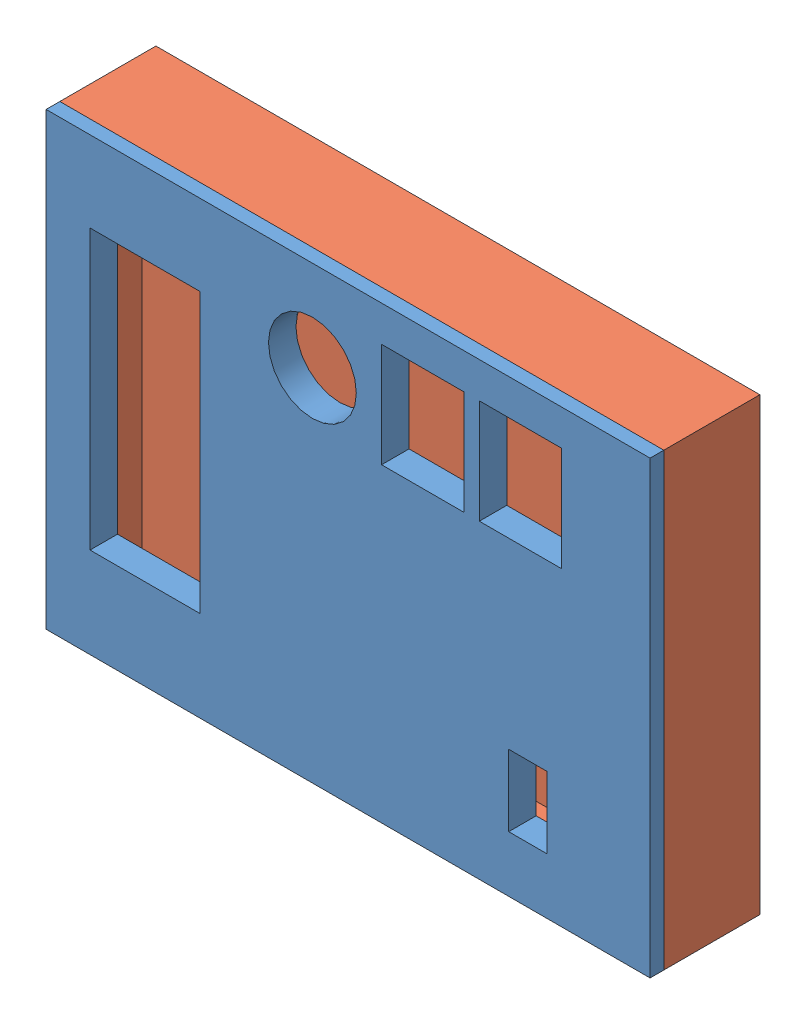
SolidWorks assembly Phase_B_Encloser_ASM.STEP, configuration Default. Lengths in mm.
Overall size (110 82 20).
50 component instances, 3 part files, 3 mates.
Components (placement in the parent):
- R_0805_2012Metric.STEP-1: R_0805_2012Metric.STEP [Default] at (136.75 -75.9525 1.63) x (0 1 0) z (0 0 1) size (2 1.2 0.45) (suppressed, hidden)
- PinSocket_2x03_P2.54mm_Vertical.STEP-1: PinSocket_2x03_P2.54mm_Vertical.STEP [Default] at (166.9225 -107.335 1.13) x (-1 0 0) z (0 0 -1) size (5.08 7.62 10.1) (suppressed, hidden)
- C_0603_1608Metric.STEP-1: C_0603_1608Metric.STEP [Default] at (175.1083 -95.3579 1.63) x (0 1 0) z (0 0 1) size (1.6 0.8 0.8) (suppressed, hidden)
- C_0603_1608Metric.STEP-2: C_0603_1608Metric.STEP [Default] at (167.3681 -95.3139 1.63) x (0 1 0) z (0 0 1) size (1.6 0.8 0.8) (suppressed, hidden)
- R_0603_1608Metric.STEP-1: R_0603_1608Metric.STEP [Default] at (178.1154 -121.5005 1.63) size (1.6 0.8 0.45) (suppressed, hidden)
- R_0805_2012Metric.STEP-2: R_0805_2012Metric.STEP [Default] at (164.6638 -86.8628 1.63) size (2 1.2 0.45) (suppressed, hidden)
- USB_Mini-B_Lumberg_2486_01_Horizontal.STEP-1: USB_Mini-B_Lumberg_2486_01_Horizontal.STEP [Default] at (156.7225 -119.07 1.63) size (9.9 9.21 5) (suppressed, hidden)
- SOT-23-5.STEP-1: SOT-23-5.STEP [Default] at (160.6831 -79.2295 1.63) x (0 -1 0) z (0 0 1) size (2.8 2.9 1.55) (suppressed, hidden)
- R_0805_2012Metric.STEP-3: R_0805_2012Metric.STEP [Default] at (124.46 -81.28 1.63) size (2 1.2 0.45) (suppressed, hidden)
- TQFP-44_10x10mm_P0.8mm.STEP-1: TQFP-44_10x10mm_P0.8mm.STEP [Default] at (154.94 -91.44 1.63) x (0 1 0) z (0 0 1) size (12 12 1.1) (suppressed, hidden)
- LED_0805_2012Metric.STEP-1: LED_0805_2012Metric.STEP [Default] at (136.66 -80.3425 1.63) x (0 1 0) z (0 0 1) size (2 1.25 1.1) (suppressed, hidden)
- C_0603_1608Metric.STEP-3: C_0603_1608Metric.STEP [Default] at (164.6143 -92.9198 1.63) size (1.6 0.8 0.8) (suppressed, hidden)
- CA56-12EWA.STEP-1: CA56-12EWA.STEP [Default] at (101.6 -81.28 1.63) size (19 50.3 12.2) (suppressed, hidden)
- C_0603_1608Metric.STEP-4: C_0603_1608Metric.STEP [Default] at (160.3412 -83.2998 1.63) x (-1 0 0) z (0 0 1) size (1.6 0.8 0.8) (suppressed, hidden)
- TSSOP-16_4.4x5mm_P0.65mm.STEP-1: TSSOP-16_4.4x5mm_P0.65mm.STEP [Default] at (137.16 -93.98 1.63) size (6.4 5 1.1) (suppressed, hidden)
- PTS125_SMD_Button.STEP-1: PTS125_SMD_Button.STEP [Default] at (177.0425 -64.155 1.63) x (0 1 0) z (1 0 0) size (12 4.3 15.3) (suppressed, hidden)
- C_0603_1608Metric.STEP-5: C_0603_1608Metric.STEP [Default] at (171.2411 -95.3579 1.63) x (0 1 0) z (0 0 1) size (1.6 0.8 0.8) (suppressed, hidden)
- R_0603_1608Metric.STEP-2: R_0603_1608Metric.STEP [Default] at (171.895 -101.6 1.63) size (1.6 0.8 0.45) (suppressed, hidden)
- C_0603_1608Metric.STEP-6: C_0603_1608Metric.STEP [Default] at (135.1928 -99.8408 1.63) x (-1 0 0) z (0 0 1) size (1.6 0.8 0.8) (suppressed, hidden)
- C_0805_2012Metric.STEP-1: C_0805_2012Metric.STEP [Default] at (177.4051 -95.4592 1.63) x (0 1 0) z (0 0 1) size (2 1.25 1.25) (suppressed, hidden)
- R_0805_2012Metric.STEP-4: R_0805_2012Metric.STEP [Default] at (124.46 -96.93 1.63) size (2 1.2 0.45) (suppressed, hidden)
- R_0805_2012Metric.STEP-5: R_0805_2012Metric.STEP [Default] at (124.46 -99.88 1.63) size (2 1.2 0.45) (suppressed, hidden)
- Buzzer_12x9.5RM7.6.STEP-1: Buzzer_12x9.5RM7.6.STEP [Default] at (139.7 -67.955 1.63) x (0 1 0) z (0 0 1) size (12 12 12.53) (suppressed, hidden)
- R_0603_1608Metric.STEP-3: R_0603_1608Metric.STEP [Default] at (164.621 -94.7272 1.63) x (-1 0 0) z (0 0 1) size (1.6 0.8 0.45) (suppressed, hidden)
- LED_0805_2012Metric.STEP-2: LED_0805_2012Metric.STEP [Default] at (139.7 -80.3425 1.63) x (0 1 0) z (0 0 1) size (2 1.25 1.1) (suppressed, hidden)
- R_0603_1608Metric.STEP-4: R_0603_1608Metric.STEP [Default] at (157.3461 -113.1038 1.63) x (0 1 0) z (0 0 1) size (1.6 0.8 0.45) (suppressed, hidden)
- R_0805_2012Metric.STEP-6: R_0805_2012Metric.STEP [Default] at (164.6674 -88.9903 1.63) size (2 1.2 0.45) (suppressed, hidden)
- C_0603_1608Metric.STEP-7: C_0603_1608Metric.STEP [Default] at (173.1422 -95.3579 1.63) x (0 1 0) z (0 0 1) size (1.6 0.8 0.8) (suppressed, hidden)
- C_0603_1608Metric.STEP-8: C_0603_1608Metric.STEP [Default] at (183.7777 -121.5005 1.63) size (1.6 0.8 0.8) (suppressed, hidden)
- Crystal_SMD_Abracon_ABM8G-4Pin_3.2x2.5mm.STEP-1: Crystal_SMD_Abracon_ABM8G-4Pin_3.2x2.5mm.STEP [Default] at (160.167 -106.8176 1.63) x (0 1 0) z (0 0 1) size (3.2 2.5 0.64) (suppressed, hidden)
- R_0805_2012Metric.STEP-7: R_0805_2012Metric.STEP [Default] at (124.46 -78.33 1.63) size (2 1.2 0.45) (suppressed, hidden)
- R_0805_2012Metric.STEP-8: R_0805_2012Metric.STEP [Default] at (139.7 -75.9525 1.63) x (0 1 0) z (0 0 1) size (2 1.2 0.45) (suppressed, hidden)
- R_0805_2012Metric.STEP-9: R_0805_2012Metric.STEP [Default] at (124.46 -93.98 1.63) size (2 1.2 0.45) (suppressed, hidden)
- C_0603_1608Metric.STEP-9: C_0603_1608Metric.STEP [Default] at (164.6119 -91.194 1.63) x (-1 0 0) z (0 0 1) size (1.6 0.8 0.8) (suppressed, hidden)
- C_0603_1608Metric.STEP-10: C_0603_1608Metric.STEP [Default] at (147.6552 -103.0061 1.63) x (0 -1 0) z (0 0 1) size (1.6 0.8 0.8) (suppressed, hidden)
- C_0603_1608Metric.STEP-11: C_0603_1608Metric.STEP [Default] at (164.2172 -77.2255 1.63) x (0 -1 0) z (0 0 1) size (1.6 0.8 0.8) (suppressed, hidden)
- C_0603_1608Metric.STEP-12: C_0603_1608Metric.STEP [Default] at (169.3071 -95.3345 1.63) x (0 1 0) z (0 0 1) size (1.6 0.8 0.8) (suppressed, hidden)
- C_0603_1608Metric.STEP-13: C_0603_1608Metric.STEP [Default] at (156.1028 -99.9047 1.63) x (0 1 0) z (0 0 1) size (1.6 0.8 0.8) (suppressed, hidden)
- SOT-23-6.STEP-1: SOT-23-6.STEP [Default] at (156.0168 -106.7769 1.63) x (0 1 0) z (0 0 1) size (2.8 2.9 1.55) (suppressed, hidden)
- R_0805_2012Metric.STEP-10: R_0805_2012Metric.STEP [Default] at (124.46 -91.03 1.63) size (2 1.2 0.45) (suppressed, hidden)
- R_0805_2012Metric.STEP-11: R_0805_2012Metric.STEP [Default] at (124.46 -84.23 1.63) size (2 1.2 0.45) (suppressed, hidden)
- C_0603_1608Metric.STEP-14: C_0603_1608Metric.STEP [Default] at (166.5378 -77.2117 1.63) x (0 -1 0) z (0 0 1) size (1.6 0.8 0.8) (suppressed, hidden)
- R_0805_2012Metric.STEP-12: R_0805_2012Metric.STEP [Default] at (124.46 -87.18 1.63) size (2 1.2 0.45) (suppressed, hidden)
- PinSocket_2x04_P2.54mm_Vertical.STEP-1: PinSocket_2x04_P2.54mm_Vertical.STEP [Default] at (179.5825 -109.875 1.63) size (5.08 10.16 10.1) (suppressed, hidden)
- LED_0805_2012Metric.STEP-3: LED_0805_2012Metric.STEP [Default] at (184.4796 -109.4399 1.63) size (2 1.25 1.1) (suppressed, hidden)
- R_0603_1608Metric.STEP-5: R_0603_1608Metric.STEP [Default] at (155.706 -113.0772 1.63) x (0 1 0) z (0 0 1) size (1.6 0.8 0.45) (suppressed, hidden)
- PTS125_SMD_Button.STEP-2: PTS125_SMD_Button.STEP [Default] at (159.2625 -64.155 1.63) x (0 1 0) z (1 0 0) size (12 4.3 15.3) (suppressed, hidden)
- PCB.STEP-1: PCB.STEP [Default] at origin (suppressed, hidden)
- Enclosure_Part_Two-1: Enclosure_Part_Two [Default] at (146.2275 -89.1522 14.2277) x (1 0 0) z (0 0 -1) size (110 82 5)
- Encloser_Part_One-1: Encloser_Part_One [Default] at (146.2275 -89.1522 -5.7723) size (110 82 17.5)
Mates (geometry in assembly coordinates):
- Coincident1: coincident anti-aligned: plane of Enclosure_Part_Two-1 through (146.1152 -88.5497 14.0488) normal (0 0 -1); line of Encloser_Part_One-1 through (224.8768 -47.6092 14.0488) axis (-1 0 0)
- Coincident2: coincident: point of Enclosure_Part_Two-1; unknown of Encloser_Part_One-1
- Distance1: distance = 1 mm: unknown of PinSocket_2x03_P2.54mm_Vertical.STEP-1/SOLID-0.STEP-1; unknown of Encloser_Part_One-1
